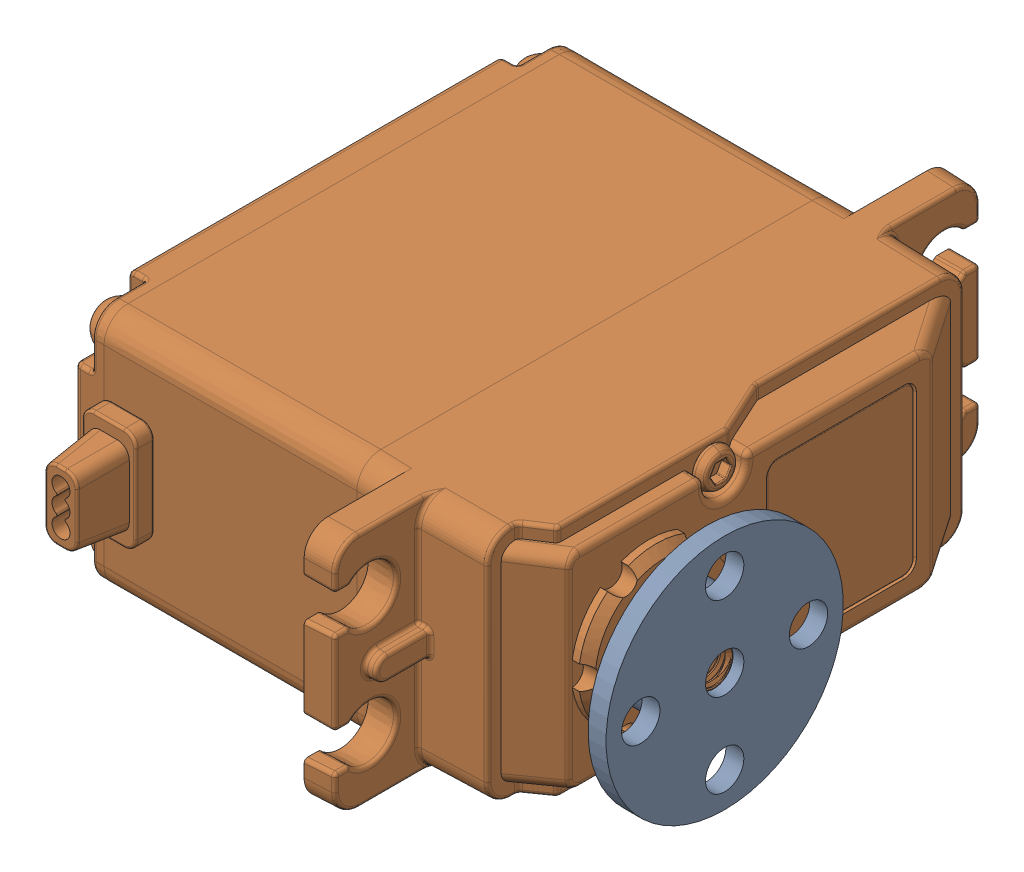
SolidWorks assembly Motor_with_horn, configuration Default. Lengths in mm.
Overall size (44.1 20.42 54.06).
2 component instances, 2 part files, 2 mates.
Components (placement in the parent):
- HSO07-1: HSO07 [Default] at (130.6726 -35.3061 144.878) x (0 0 -1) z (0 1 0) size (19.8 5 19.8)
- AGF B53-whole-1: AGF B53-whole [Default] at (110.1726 -35.3061 135.078) x (0 0 -1) z (0 -1 0) size (54.06 43.31 20.42)
Mates (geometry in assembly coordinates):
- Coincident1: coincident anti-aligned: plane of HSO07-1 through (125.6726 -35.3061 144.878) normal (-1 0 0); plane of AGF B53-whole-1 through (125.6726 -35.3061 135.078) normal (1 0 0)
- Concentric1: concentric aligned: circle of HSO07-1; circle of AGF B53-whole-1
